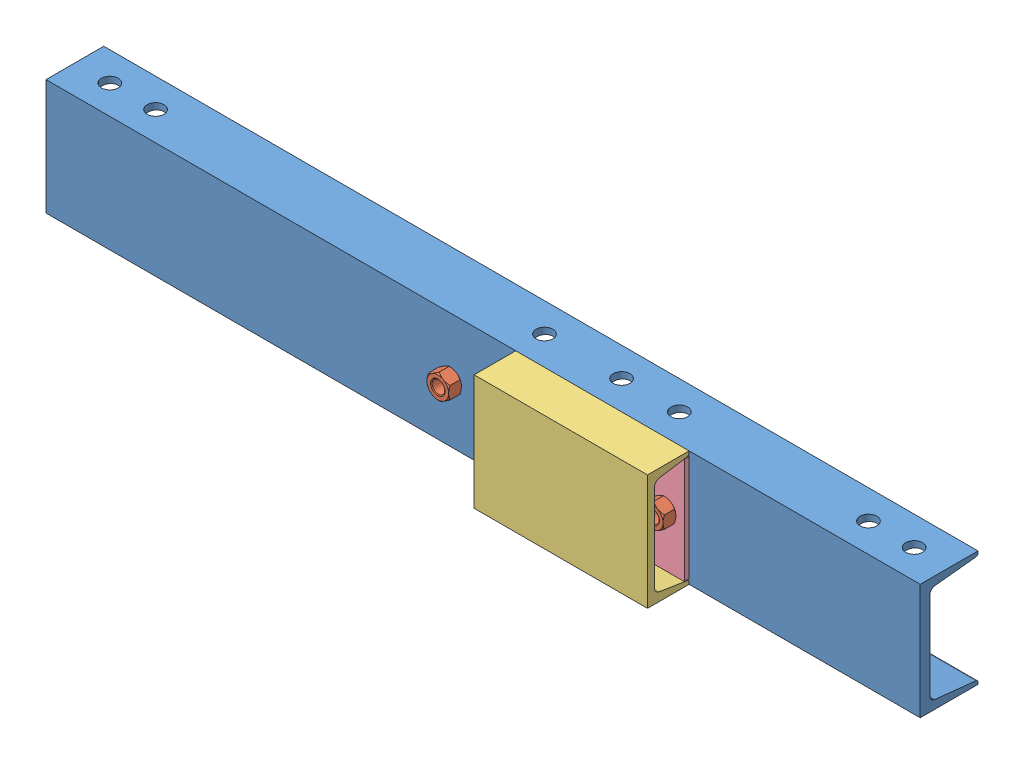
SolidWorks assembly 01-116-00-0, configuration Default. Lengths in mm.
Overall size (1152.53 152.4 131.06).
7 component instances, 4 part files, 16 mates.
Components (placement in the parent):
- 01-115-00-0-1: 01-115-00-0 [Default] at (0 -25.3019 0) size (1152.53 152.4 76.2)
- hex nut_ai-1: hex nut_ai [HNUT 0.7500-10-D-C] at (-42.8625 -25.3019 65.6971) size (28.57 33 16.89)
- 01-034-00-0-1: 01-034-00-0 [Default] at (157.2895 -25.3019 78.3336) size (228.6 152.4 54.86)
- Compression Spacer backing plate-1: Compression Spacer backing plate [Default] at (271.5895 -95.1519 55.1561) x (0 1 0) z (-1 0 0) size (139.7 6.35 50.8)
- Compression Spacer backing plate-2: Compression Spacer backing plate [Default] at (93.7895 44.5481 48.8061) x (0 -1 0) z (-1 0 0) size (139.7 6.35 50.8)
- hex nut_ai-2: hex nut_ai [HNUT 0.7500-10-D-C] at (68.3895 -25.3019 72.0471) size (28.57 33 16.89)
- hex nut_ai-3: hex nut_ai [HNUT 0.7500-10-D-C] at (246.1895 -25.3019 72.0471) size (28.57 33 16.89)
Mates (geometry in assembly coordinates):
- Concentric11: concentric: cylinder of 01-115-00-0-1 through (-82.55 0 27.3949) axis (0 0 -1) radius 9.525; cylinder of hex nut_ai-1 through (-82.55 0 19.2474) axis (0 0 1) radius 9.525
- Coincident11: coincident anti-aligned: plane of 01-115-00-0-1 through (576.2625 -101.5019 48.8061) normal (0 0 1); plane of hex nut_ai-1 through (-42.8625 -8.8041 48.8061) normal (0 0 -1)
- Coincident1125: coincident anti-aligned: plane of 01-115-00-0-1 through (576.2625 -101.5019 48.8061) normal (0 0 1); plane of 01-034-00-0-1 through (271.5895 -101.5019 48.8061) normal (0 0 -1)
- Distance1: distance = 847.852 mm anti-aligned: plane of 01-034-00-0-1 through (271.5895 -99.0126 51.8541) normal (1 0 0); plane of 01-115-00-0-1 through (-576.2625 -99.0126 -24.3459) normal (-1 0 0)
- Concentric12: concentric anti-aligned: cylinder of 01-115-00-0-1 through (-42.8625 -25.3019 48.8061) axis (0 0 -1) radius 11.1125; cylinder of hex nut_ai-1 through (-42.8625 -25.3019 48.8061) axis (0 0 1) radius 8.3337
- Coincident1129: coincident anti-aligned: plane of 01-115-00-0-1 through (576.2625 -101.5019 48.8061) normal (0 0 1); plane of Compression Spacer backing plate-1 through (271.5895 -95.1519 48.8061) normal (0 0 -1)
- Coincident1130: coincident aligned: plane of 01-034-00-0-1 through (271.5895 -99.0126 51.8541) normal (1 0 0); plane of Compression Spacer backing plate-1 through (271.5895 -95.1519 48.8061) normal (1 0 0)
- Distance3: distance = 6.35 mm aligned: plane of Compression Spacer backing plate-1 through (271.5895 -95.1519 48.8061) normal (0 -1 0); plane of 01-115-00-0-1 through (576.2625 -101.5019 48.8061) normal (0 -1 0)
- Coincident1133: coincident anti-aligned: plane of 01-115-00-0-1 through (576.2625 -101.5019 48.8061) normal (0 0 1); plane of Compression Spacer backing plate-2 through (93.7895 44.5481 48.8061) normal (0 0 -1)
- Coincident1134: coincident aligned: plane of 01-034-00-0-1 through (42.9895 -99.0126 51.8541) normal (-1 0 0); plane of Compression Spacer backing plate-2 through (42.9895 44.5481 55.1561) normal (-1 0 0)
- Distance4: distance = 6.35 mm aligned: plane of Compression Spacer backing plate-2 through (93.7895 -95.1519 55.1561) normal (0 -1 0); plane of 01-115-00-0-1 through (576.2625 -101.5019 48.8061) normal (0 -1 0)
- Coincident1136: coincident aligned: plane of 01-115-00-0-1 through (576.2625 -101.5019 48.8061) normal (0 -1 0); plane of 01-034-00-0-1 through (271.5895 -101.5019 103.6701) normal (0 -1 0)
- Concentric131: concentric aligned: cylinder of Compression Spacer backing plate-2 through (68.3895 -25.3019 48.8061) axis (0 0 1) radius 11.1125; cylinder of hex nut_ai-2 through (68.3895 -25.3019 47.0096) axis (0 0 1) radius 9.525
- Coincident11371: coincident anti-aligned: plane of Compression Spacer backing plate-2 through (93.7895 44.5481 55.1561) normal (0 0 1); plane of hex nut_ai-2 through (68.3895 -8.8041 55.1561) normal (0 0 -1)
- Concentric141: concentric anti-aligned: cylinder of Compression Spacer backing plate-1 through (246.1895 -25.3019 55.1561) axis (0 0 -1) radius 11.1125; cylinder of hex nut_ai-3 through (246.1895 -25.3019 47.0096) axis (0 0 1) radius 9.525
- Coincident11381: coincident anti-aligned: plane of Compression Spacer backing plate-1 through (271.5895 -95.1519 55.1561) normal (0 0 1); plane of hex nut_ai-3 through (246.1895 -8.8041 55.1561) normal (0 0 -1)
